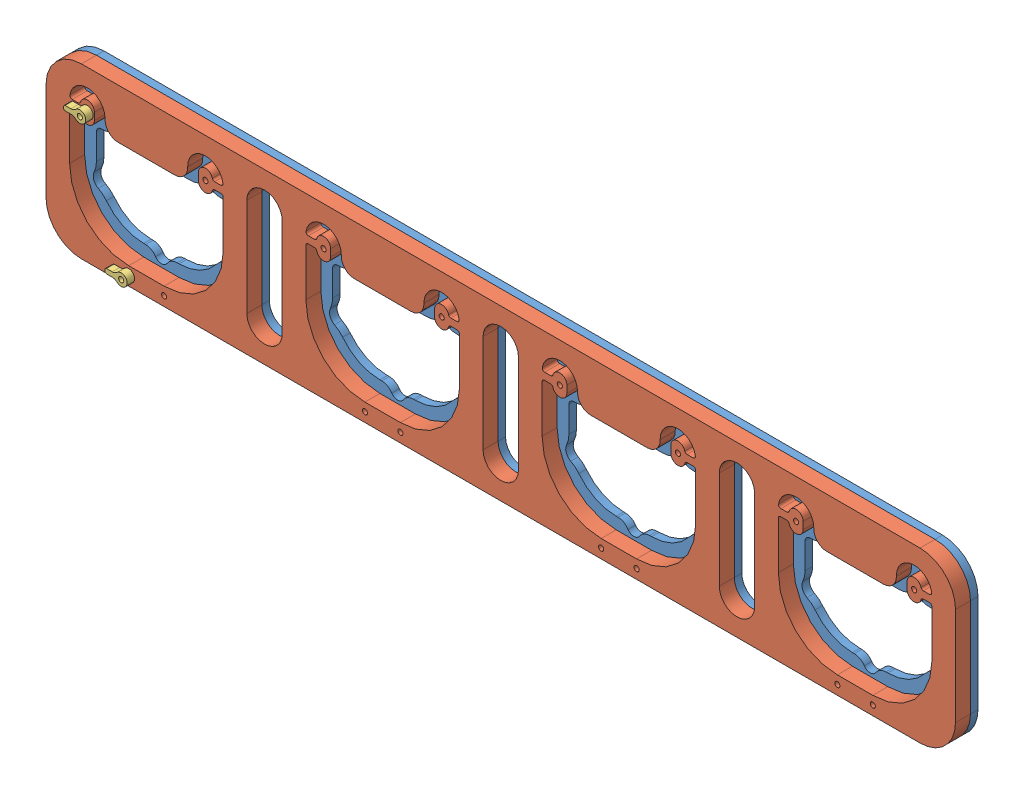
SolidWorks assembly RackMock, configuration Default. Lengths in mm.
Overall size (385 71.5 12.7).
4 component instances, 3 part files, 6 mates.
Components (placement in the parent):
- LowerRack-1: LowerRack [Default] at (-10.5275 219.5263 303.8552) size (385 71.5 3.17)
- TopRack-1: TopRack [Default] at (-10.5275 219.5263 307.0302) size (385 71.5 6.35)
- Latch-1: Latch [Default] at (-112.7158 182.3511 313.3802) size (9.37 5 3.17)
- Latch-2: Latch [Default] at (-130.2158 233.3859 313.3802) size (9.37 5 3.17)
Mates (geometry in assembly coordinates):
- Coincident1: coincident anti-aligned: plane of LowerRack-1 through (-31.3236 254.4407 307.0302) normal (0 0 1); plane of TopRack-1 through (-31.3236 254.4407 307.0302) normal (0 0 -1)
- Concentric1: concentric aligned: cylinder of LowerRack-1 through (-11.3236 201.906 307.0302) axis (0 0 -1) radius 0.889; cylinder of TopRack-1 through (-11.3236 201.906 313.3802) axis (0 0 -1) radius 1.0922
- Coincident2: coincident anti-aligned: plane of TopRack-1 through (-31.3236 254.4407 313.3802) normal (0 0 1); plane of Latch-2 through (-32.5985 248.9407 313.3802) normal (0 0 -1)
- Coincident3: coincident anti-aligned: circle of TopRack-1; cylinder of Latch-2 through (-28.8236 252.9407 316.5552) axis (0 0 -1) radius 1.0922
- Coincident5: coincident: plane of TopRack-1 through (-31.3236 254.4407 313.3802) normal (0 0 1); plane of Latch-1 through (-15.0985 197.906 313.3802) normal (0 0 -1)
- Concentric2: concentric aligned: cylinder of TopRack-1 through (-11.3236 201.906 313.3802) axis (0 0 -1) radius 1.0922; cylinder of Latch-1 through (-11.3236 201.906 316.5552) axis (0 0 -1) radius 1.0922
